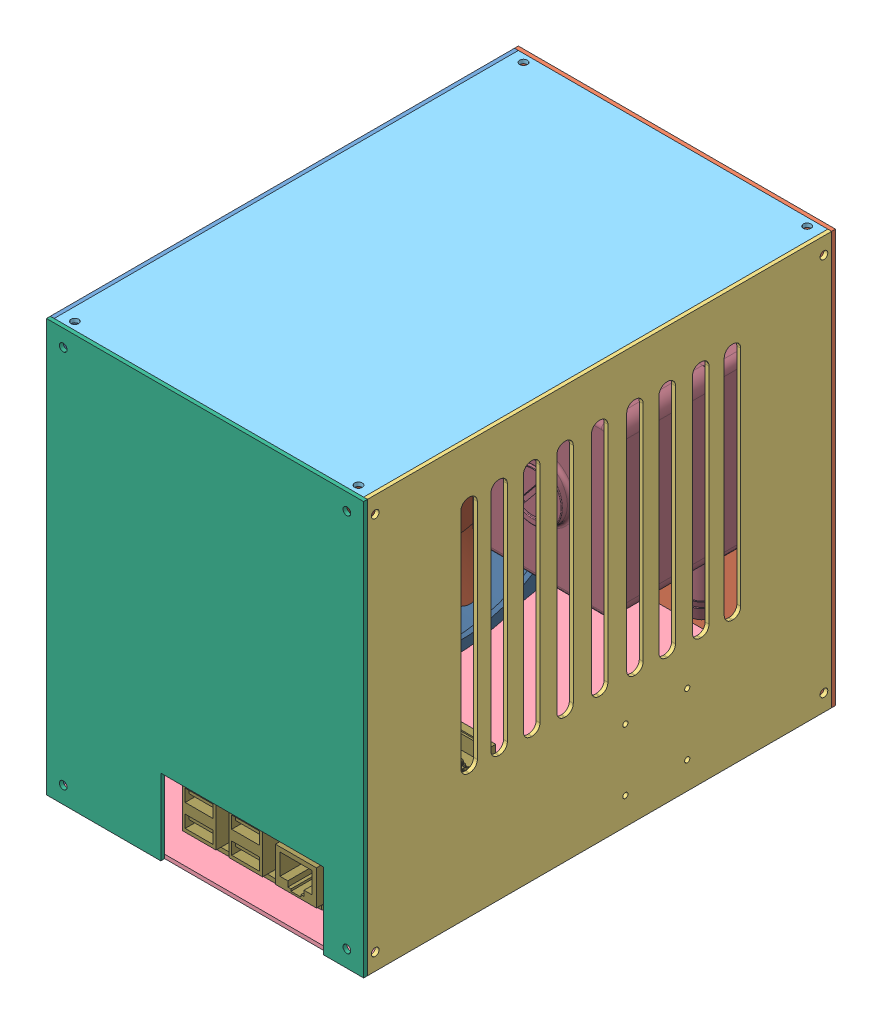
SolidWorks assembly testfitting, configuration 默认. Lengths in mm.
Overall size (209.72 249.7 249.7).
16 component instances, 16 part files, 26 mates.
Components (placement in the parent):
- backpanel-1: backpanel [默认] at (209.3731 1054.6647 33.5167) x (0 1 0) z (1 0 0) size (160 180 1.5)
- bottompanel-1: bottompanel [默认] at (-1416.1798 -809.449 -42.1872) x (0 1 0) z (0 0 1) size (160 123 1.5)
- frontpanel-1: frontpanel [默认] at (330.8731 2933.2289 59.2372) x (0 -1 0) z (1 0 0) size (160 180 1.5)
- sidepanel_mount-1: sidepanel_mount [默认] at (-639.5491 265.4094 50.2568) x (1 0 0) z (0 -1 0) size (120 180 1.5)
- sidepanel_normal-1: sidepanel_normal [默认] at (-3889.9462 423.9094 40.4498) x (1 0 0) z (0 -1 0) size (120 180 1.5)
- top_IO_panel-1: top_IO_panel [默认] at (-1416.1798 -809.449 139.3128) x (0 1 0) z (0 0 1) size (160 123 1.5)
- sit.stp-1: sit.stp [默认] at (284.8793 264.6594 193.5585) x (-1 0 -0.000999) z (0 1 0) size (6.41 6.41 8.27)
- sit - 副本.stp-1: sit - 副本.stp [默认] at (230.8754 264.6594 133.1481) x (-0.996473 0 -0.08391) z (0 1 0) size (6.41 6.41 8.27)
- MCR120-1: MCR120 [Default] at (228.6231 353.1594 -25.4372) x (0 -1 0) z (0 0 -1) size (128 34.16 162)
- Corsair AF120 FanEnclosure-1: Corsair AF120 FanEnclosure [Default] at (272.6231 353.1594 45.0628) x (0 -1 0) z (0 0 -1) size (120 29 120)
- Corsair AF120 FanBlade-2: Corsair AF120 FanBlade [Default] at (250.6231 353.1594 45.0628) x (0 0 1) z (0 1 0) size (249.7 209.72 249.7)
- Raspberry Pi 4 B-1: Raspberry Pi 4 B [默认] at (271.8039 271.5304 98.8965) x (0 0 1) z (0 1 0) size (86.92 58.6 19)
- SC-300T Dummy-1: SC-300T Dummy [Standard] at (301.7882 362.3758 -37.8172) x (1 0 0) z (0 -1 0) size (56 84.77 89.25)
- oledsit.stp-1: oledsit.stp [默认] at (331.6231 337.2159 41.8228) x (0 0 1) z (-1 0 0) size (6.41 6.41 8.27)
- oledsit2.stp-1: oledsit2.stp [默认] at (331.6231 361.1013 65.4011) x (0 0 1) z (-1 0 0) size (6.41 6.41 8.27)
- 0.96 OLED v3.step-1: 0.96 OLED v3.step [默认] at (323.3521 285.6757 28.0143) x (0 1 0) z (1 0 0) size (28 28 11)
Mates (geometry in assembly coordinates):
- 重合2: coincident anti-aligned: plane of backpanel-1 through (211.6231 263.1594 -39.9372) normal (0 0 -1); plane of bottompanel-1 through (102.8428 227.8985 -39.9372) normal (0 0 1)
- 重合3: coincident anti-aligned: line of backpanel-1 through (210.1231 263.1594 -39.9372) axis (0 1 0); line of bottompanel-1 through (210.1231 423.1594 -39.9372) axis (0 -1 0)
- 重合4: coincident anti-aligned: line of backpanel-1 through (211.6231 263.1594 -39.9372) axis (-1 0 0); line of bottompanel-1 through (210.1231 263.1594 -39.9372) axis (1 0 0)
- 重合5: coincident anti-aligned: plane of bottompanel-1 through (102.8428 227.8985 -39.9372) normal (0 0 1); plane of sidepanel_normal-1 through (211.6231 421.6594 -39.9372) normal (0 0 -1)
- 重合6: coincident anti-aligned: line of bottompanel-1 through (333.1231 423.1594 -39.9372) axis (-1 0 0); line of sidepanel_normal-1 through (211.6231 423.1594 -39.9372) axis (1 0 0)
- 重合7: coincident anti-aligned: line of backpanel-1 through (211.6231 423.1594 -39.9372) axis (0 0 1); line of sidepanel_normal-1 through (211.6231 423.1594 140.0628) axis (0 0 -1)
- 重合13: coincident anti-aligned: plane of backpanel-1 through (211.6231 412.1663 50.0628) normal (1 0 0); plane of sidepanel_mount-1 through (211.6231 263.1594 140.0628) normal (-1 0 0)
- 重合14: coincident aligned: line of bottompanel-1 through (210.1231 263.1594 -39.9372) axis (1 0 0); line of sidepanel_mount-1 through (211.6231 263.1594 -39.9372) axis (1 0 0)
- 重合22: coincident anti-aligned: plane of sidepanel_mount-1 through (180.4778 264.6594 50.0628) normal (0 1 0); plane of sit - 副本.stp-1 through (265.4228 264.6594 76.1426) normal (0 -1 0)
- 重合23: coincident aligned: line of backpanel-1 through (211.6231 263.1594 140.0628) axis (0 0 -1); line of sidepanel_mount-1 through (211.6231 263.1594 140.0628) axis (0 0 -1)
- 重合24: coincident anti-aligned: plane of backpanel-1 through (211.6231 412.1663 50.0628) normal (1 0 0); plane of MCR120-1 through (211.6231 417.1594 -18.4372) normal (-1 0 0)
- 同心1: concentric anti-aligned: circle of backpanel-1; circle of MCR120-1
- 重合25: coincident anti-aligned: plane of sidepanel_mount-1 through (180.4778 264.6594 50.0628) normal (0 1 0); plane of sit.stp-1 through (314.5812 264.6594 133.8848) normal (0 -1 0)
- 重合26: coincident anti-aligned: plane of MCR120-1 through (245.6231 417.1594 -18.4372) normal (1 0 0); plane of Corsair AF120 FanEnclosure-1 through (245.6231 353.1594 45.0628) normal (-1 0 0)
- 同心2: concentric anti-aligned: cylinder of MCR120-1; cylinder of Corsair AF120 FanEnclosure-1 through (245.6231 300.6594 97.5628) axis (1 0 0) radius 1.6
- 同心3: concentric anti-aligned: circle of Corsair AF120 FanEnclosure-1; circle of Corsair AF120 FanBlade-2
- 重合28: coincident aligned: plane of sit.stp-1 through (314.5812 272.9304 133.8848) normal (0 1 0); plane of Raspberry Pi 4 B-1 through (312.7666 272.9304 113.651) normal (0 1 0)
- 重合30: coincident anti-aligned: plane of bottompanel-1 through (102.8428 227.8985 -39.9372) normal (0 0 1); plane of SC-300T Dummy-1 through (295.9082 348.7158 -39.9372) normal (0 0 -1)
- 重合31: coincident aligned: line of bottompanel-1 through (333.1231 263.1594 -39.9372) axis (0 1 0); line of frontpanel-1 through (333.1231 263.1594 -39.9372) axis (0 1 0)
- 重合32: coincident anti-aligned: plane of bottompanel-1 through (102.8428 227.8985 -39.9372) normal (0 0 1); plane of frontpanel-1 through (333.1231 263.1594 -39.9372) normal (0 0 -1)
- 重合33: coincident anti-aligned: line of frontpanel-1 through (331.6231 263.1594 140.0628) axis (0 0 -1); line of sidepanel_mount-1 through (331.6231 263.1594 -39.9372) axis (0 0 1)
- 重合35: coincident anti-aligned: line of frontpanel-1 through (333.1231 423.1594 140.0628) axis (0 -1 0); line of top_IO_panel-1 through (333.1231 263.1594 140.0628) axis (0 1 0)
- 重合36: coincident: line of sidepanel_mount-1 through (331.6231 263.1594 140.0628) axis (-1 0 0); plane of top_IO_panel-1 through (210.1231 263.1594 141.5628) normal (0 -1 0)
- 重合37: coincident anti-aligned: plane of frontpanel-1 through (331.6231 599.1641 51.0241) normal (-1 0 0); plane of oledsit2.stp-1 through (331.6231 301.398 35.7589) normal (1 0 0)
- 重合38: coincident anti-aligned: plane of frontpanel-1 through (331.6231 599.1641 51.0241) normal (-1 0 0); plane of oledsit.stp-1 through (331.6231 277.5126 12.1806) normal (1 0 0)
- 重合39: coincident anti-aligned: plane of oledsit.stp-1 through (323.3521 277.5126 12.1806) normal (-1 0 0); plane of 0.96 OLED v3.step-1 through (323.3521 285.6757 28.0143) normal (1 0 0)
